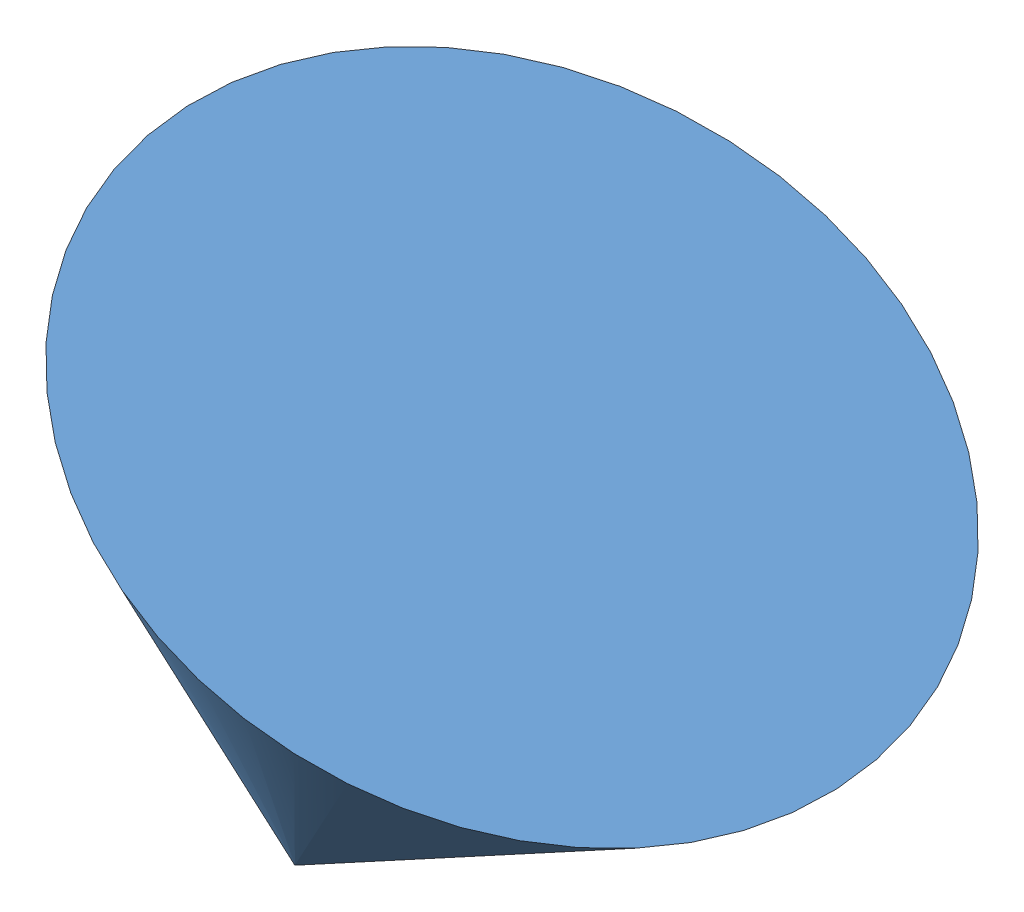
SolidWorks assembly Assem5, configuration Default. Lengths in mm.
Overall size (1036.54 389.12 144.05).
2 component instances, 2 part files, 2 mates.
Components (placement in the parent):
- path-1: path [Default] at (12.1636 407.9991 705.2572) size (971.15 358.94 0)
- Part1-1: Part1 [Default] at (983.3131 640.3754 705.2572) x (0.907526 -0.418969 0.029333) z (0.026632 -0.012295 -0.99957) size (140 105 140)
Mates (geometry in assembly coordinates):
- PathMate1: path: point of Part1-1; curve of path-1
- Coincident1: coincident: point of assembly; curve of path-1; point of Part1-1
